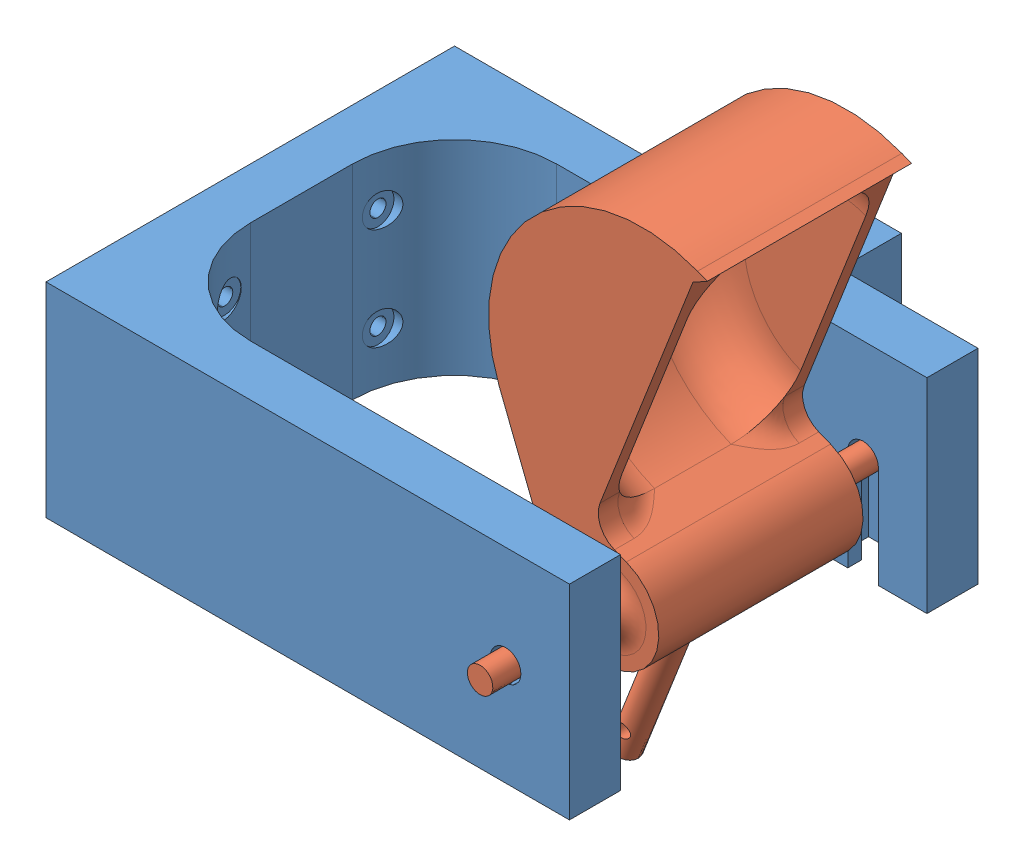
SolidWorks assembly ExcavatorTestingAssembly, configuration Default. Lengths in mm.
Overall size (157.33 155.02 123.19).
2 component instances, 2 part files, 2 mates.
Components (placement in the parent):
- ExcavationUnitTestingBracket-1: ExcavationUnitTestingBracket [Default] at origin size (130.17 50.8 116.84)
- PreliminaryExcavator-2: PreliminaryExcavator [3DPrintConfig] at (96.1946 12.3383 101.6) x (0 0 1) z (-0.931425 0.363933 0) size (114.3 142.86 60.33)
Mates (geometry in assembly coordinates):
- Concentric3: concentric aligned: cylinder of ExcavationUnitTestingBracket-1 through (101.6 0 152.4) axis (0 0 -1) radius 3.81; cylinder of PreliminaryExcavator-2 through (101.6 0 158.75) axis (0 0 -1) radius 3.175
- Distance2: distance = 6.35 mm aligned: plane of PreliminaryExcavator-2 through (101.6 0 44.45) normal (0 0 -1); plane of ExcavationUnitTestingBracket-1 through (0 0 50.8) normal (0 0 -1)
